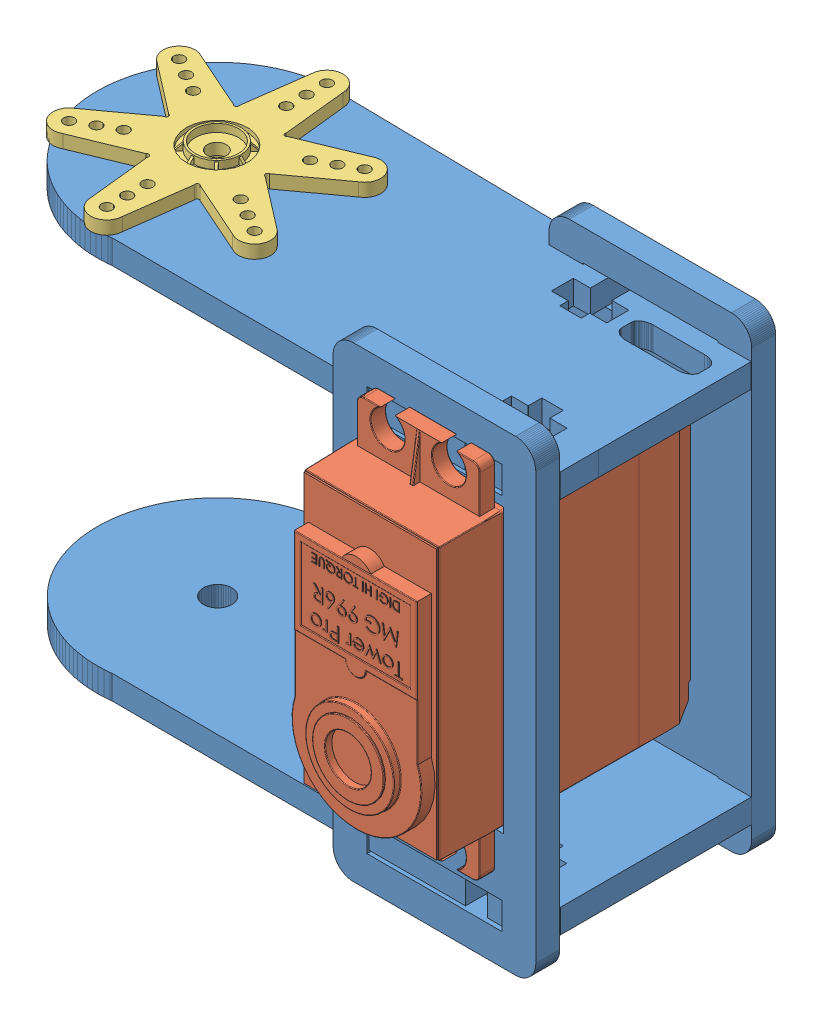
SolidWorks assembly left_hip_clamp, configuration Default. Lengths in mm.
Overall size (82.12 68.24 48.86).
4 component instances, 3 part files, 2 mates.
Components (placement in the parent):
- left_hip_pelvis_clamp_100-2: left_hip_pelvis_clamp_100 [Default] at (-91.1924 -29.3882 -88.5432) size (82.12 68.24 35.48)
- main_assembly-2: main_assembly [Default] at (-5.5402 43.085 -112.24) x (-0.999996 0 -0.002733) z (-0.002733 0 0.999996) size (20 53 41.5)
  - main_body-1: main_body [Default] at (15.1003 34.2066 38.7045) size (20 53 41.5)
- servo_arm_6_sided-3: servo_arm_6_sided [Default] at (-70.3806 34.5719 -71.4654) x (-0.013501 0 0.999909) z (-0.999909 0 -0.013501) size (36.45 6.25 32.2)
Mates (geometry in assembly coordinates):
- Coincident1: coincident anti-aligned: line of left_hip_pelvis_clamp_100-2 through (-30.8008 -11.8793 -53.6043) axis (0 1 0); line of main_assembly-2/main_body-1 through (-30.8008 28.6284 -53.6043) axis (0 -1 0)
- ProfileCenter1: profile center anti-aligned: circle of left_hip_pelvis_clamp_100-2; circle of servo_arm_6_sided-3
